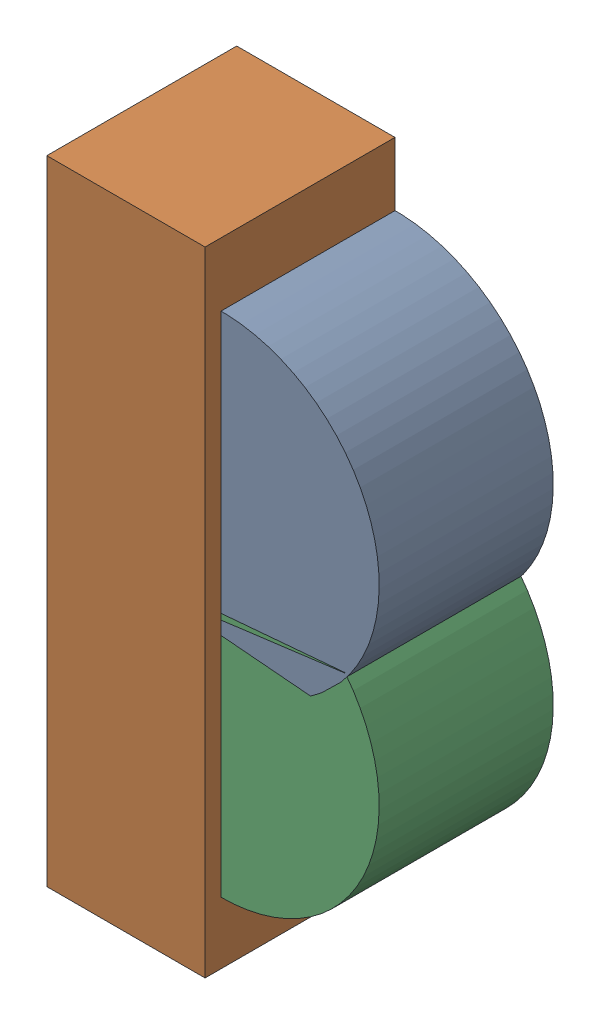
SolidWorks assembly D16, configuration Default. Lengths in mm.
Overall size (1 2 0.6).
6 component instances, 2 part files, 0 mates.
Components (placement in the parent):
- 786389736-1: 786389736 [Default] at (141.2 33.65 0) x (0 1 0) z (0 0 1) size (1 1 0.55)
  - Cylinder-1: Cylinder [Default] at origin size (1 1 0.55)
- 836753648-1: 836753648 [Default] at (140.95 33.35 0) size (0.5 2 0.6)
  - Extruded_33-1: Extruded_33 [Default] at origin size (0.5 2 0.6)
- 786389736-2: 786389736 [Default] at (141.2 33.0461 0) x (0 1 0) z (0 0 1) size (1 1 0.55)
  - Cylinder-1: Cylinder [Default] at origin size (1 1 0.55)
